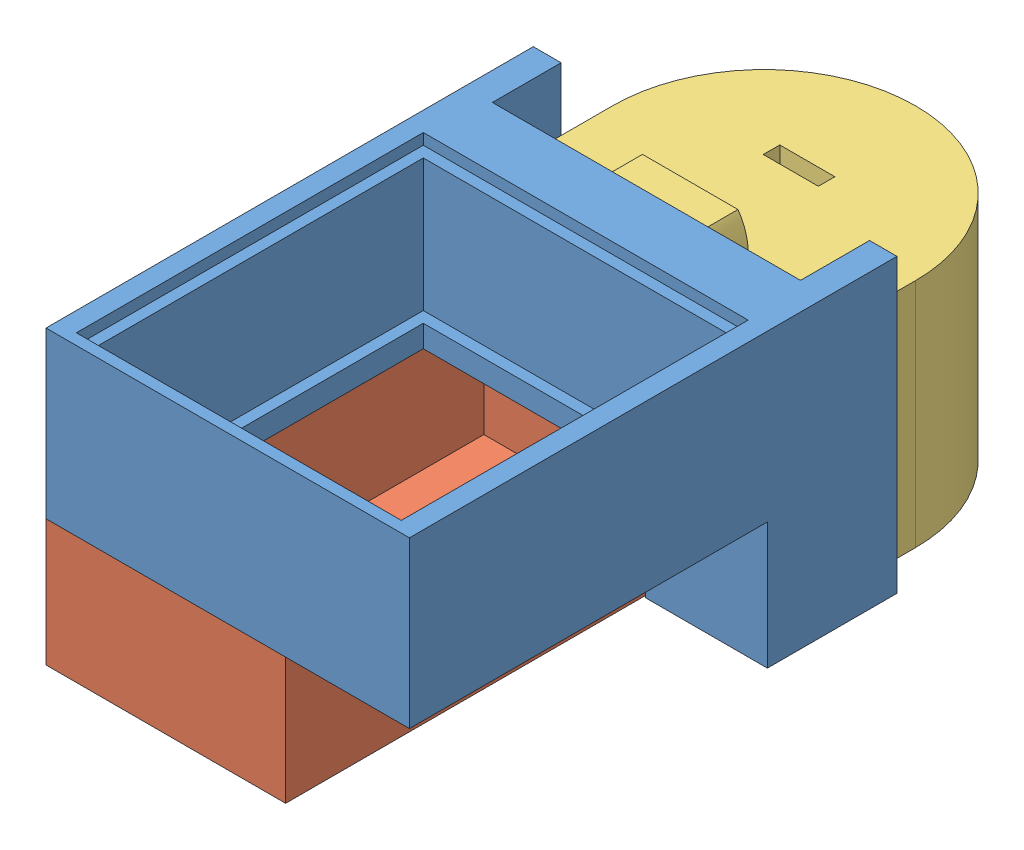
SolidWorks assembly Сборка htcbdthf, configuration По умолчанию. Lengths in mm.
Overall size (33 26.5 62.45).
3 component instances, 3 part files, 5 mates.
Components (placement in the parent):
- reviever_box-1: reviever_box [По умолчанию] at (-21.62 -2.6903 41.8975) size (33 26.5 44.27)
- reciever_box_down-1: reciever_box_down [По умолчанию] at (-67.5508 -11.1903 32.7419) x (0 0 1) z (-1 0 0) size (38 11.5 21.76)
- BAT_12V-1: BAT_12V [По умолчанию] at (-88.5528 -7.1659 19.0419) x (-1 0 0) z (0 0 -1) size (27.5 26 24.25)
Mates (geometry in assembly coordinates):
- Совпадение1: coincident anti-aligned: line of reviever_box-1 through (-68.5508 -2.6903 63.7419) axis (1 0 0); line of reciever_box_down-1 through (-52.5508 -2.6903 63.7419) axis (-1 0 0)
- Совпадение2: coincident anti-aligned: line of reviever_box-1 through (-68.5508 -2.6903 37.2419) axis (0 0 1); line of reciever_box_down-1 through (-68.5508 -2.6903 63.7419) axis (0 0 -1)
- Расстояние1: distance = 0.2 mm anti-aligned: plane of BAT_12V-1 through (-88.5528 -7.1659 29.5419) normal (0 0 1); plane of reciever_box_down-1 through (-50.5508 42.5984 29.7419) normal (0 0 -1)
- Совпадение9: coincident aligned: plane of reciever_box_down-1 through (-67.5508 -14.1903 32.7419) normal (0 -1 0); plane of BAT_12V-1 through (-55.8097 -14.1903 19.0419) normal (0 -1 0)
- Ширина1: width anti-aligned: plane of reviever_box-1 through (-72.3097 12.3097 29.7419) normal (-1 0 0); plane of reviever_box-1 through (-39.3097 12.3097 29.7419) normal (1 0 0); plane of BAT_12V-1 through (-42.0597 -14.1903 29.5419) normal (1 0 0); plane of BAT_12V-1 through (-69.5597 6.8097 29.5419) normal (-1 0 0)
